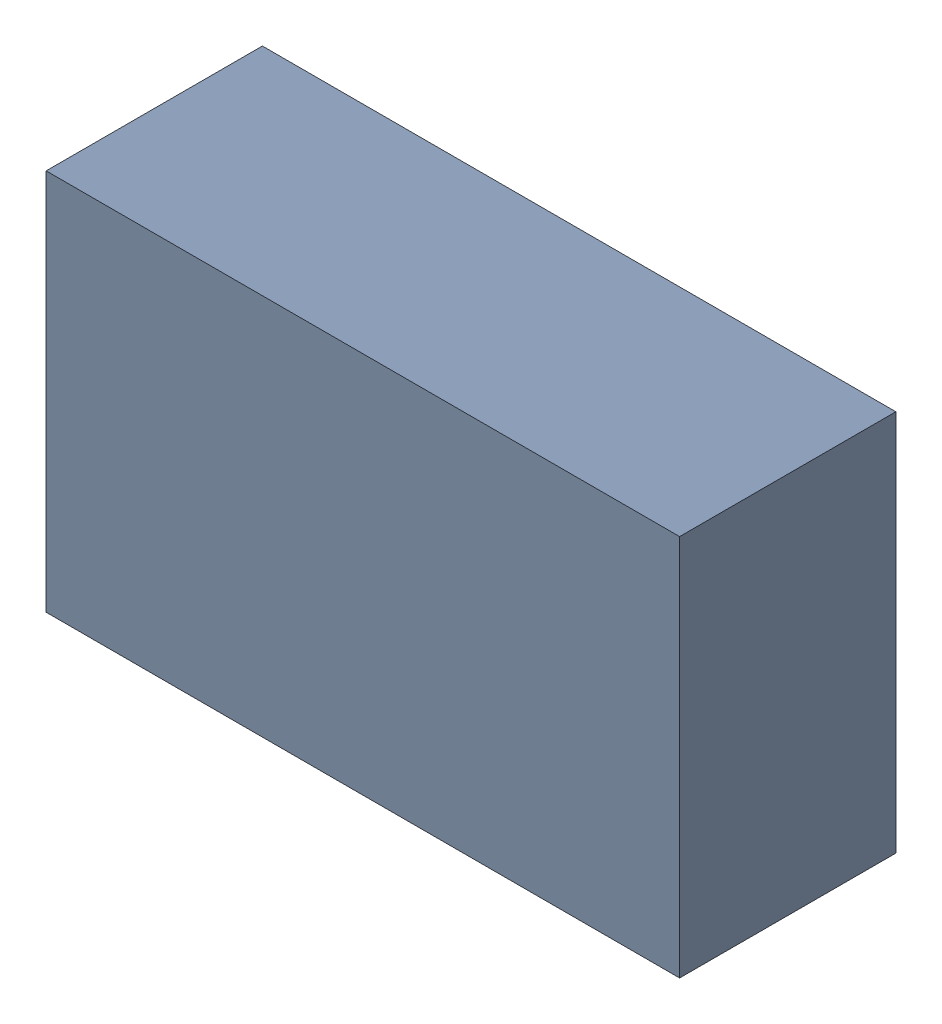
SolidWorks assembly U9, configuration Default. Lengths in mm.
Overall size (2.9 1.75 0.99).
2 component instances, 1 part files, 0 mates.
Components (placement in the parent):
- 870946400-1: 870946400 [Default] at (19.9382 34.2586 -2.6006) size (2.9 1.75 0.99)
  - Extruded_9-1: Extruded_9 [Default] at origin size (2.9 1.75 0.99)
